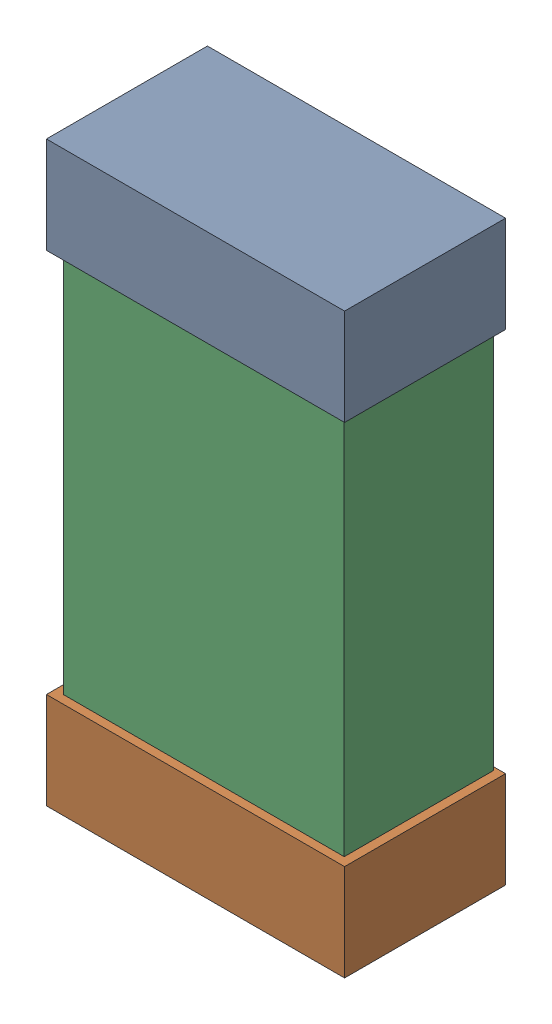
SolidWorks assembly C45, configuration Default. Lengths in mm.
Overall size (0.85 1.65 0.46).
6 component instances, 2 part files, 0 mates.
Components (placement in the parent):
- 432138512_34-1: 432138512_34 [Default] at (38.2723 41.736 -0.8715) size (0.85 0.28 0.46)
  - Extruded-1: Extruded [Default] at origin size (0.85 0.28 0.46)
- 432138512_35-1: 432138512_35 [Default] at (38.2723 40.3644 -0.8715) size (0.85 0.28 0.46)
  - Extruded-1: Extruded [Default] at origin size (0.85 0.28 0.46)
- 432124816_17-1: 432124816_17 [Default] at (38.2723 41.0502 -0.8615) size (0.8 1.5 0.42)
  - Extruded (1)-1: Extruded (1) [Default] at origin size (0.8 1.5 0.42)
